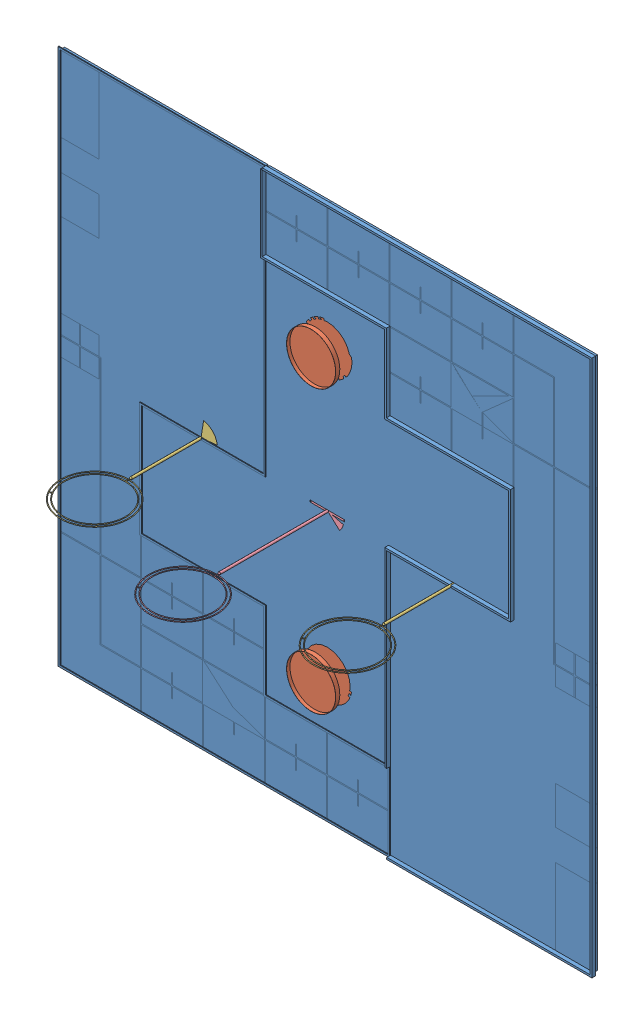
SolidWorks assembly playfieldasm, configuration Default. Lengths in mm.
Overall size (14100 14100 5035.59).
6 component instances, 4 part files, 13 mates.
Components (placement in the parent):
- playfield-1: playfield [Default] at (4070.2152 6513.5472 12026.2645) size (14100 14100 200.73)
- playfield1-1: playfield1 [Default] at (4070.2152 10213.5472 12020.8842) x (-0.989359 -0.145497 0) z (-0.145497 0.989359 0) size (1291.25 530.04 1291.25)
- playfield1-2: playfield1 [Default] at (4070.2152 2813.5472 12020.8842) x (0.949745 0.313024 0) z (0.313024 -0.949745 0) size (1291.25 530.04 1291.25)
- ss2-4: ss2 [Default] at (750.7466 6515.129 14815.9191) x (0.989949 0 0.141421) z (0.141421 0 -0.989949) size (1796 868 3819.99)
- ss2-5: ss2 [Default] at (7390.7462 6514.0213 14815.9191) x (0.989949 0 0.141421) z (0.141421 0 -0.989949) size (1796 868 3819.99)
- ss-4: ss [Default] at (4070.7462 6513.6426 15815.9191) x (0.989949 0 0.141421) z (0.141421 0 -0.989949) size (1877.72 868 4809.94)
Mates (geometry in assembly coordinates):
- Parallel1: parallel aligned: plane of playfield-1 through (4070.2152 6513.5472 11926.2645) normal (0 0 -1); plane of playfield1-1 through (4070.2152 10213.5472 11921.2645) normal (0 0 -1)
- Parallel2: parallel aligned: plane of playfield1-1 through (4070.2152 10213.5472 11921.2645) normal (0 0 -1); plane of playfield1-2 through (4070.2152 2813.5472 11921.2645) normal (0 0 -1)
- Concentric1: concentric anti-aligned: circle of playfield-1; circle of playfield1-1
- Distance2: distance = 0 mm aligned: plane of playfield1-1 through (3431.4606 10119.6105 12026.2645) normal (0 0 1); plane of playfield-1 through (4070.2152 6513.5472 12026.2645) normal (0 0 1)
- Concentric2: concentric anti-aligned: circle of playfield-1; circle of playfield1-2
- Coincident6: coincident aligned: plane of playfield-1 through (4070.2152 6513.5472 12026.2645) normal (0 0 1); plane of playfield1-2 through (4683.3944 3015.6434 12026.2645) normal (0 0 1)
- Parallel8: parallel aligned: plane of playfield-1 through (4070.2152 6513.5472 12026.2645) normal (0 0 1); plane of ss2-4 through (750.7466 6515.129 12026.2645) normal (0 0 1)
- Coincident21: coincident aligned: plane of playfield-1 through (4070.2152 6513.5472 11926.2645) normal (0 0 -1); plane of ss2-4 through (750.7466 6515.129 11926.2645) normal (0 0 -1)
- Coincident22: coincident aligned: plane of playfield-1 through (4070.2152 6513.5472 11926.2645) normal (0 0 -1); plane of ss2-5 through (7390.7462 6514.0213 11926.2645) normal (0 0 -1)
- Distance11: distance = 3260 mm: cylinder of ss2-5 through (7390.7462 6514.0213 14815.9191) axis (0 0 1) radius 30; cylinder of ss-4 through (4070.7462 6513.6426 15815.9191) axis (0 0 1) radius 30
- Lock9: lock: unknown of playfield-1; unknown of ss2-5
- Lock10: lock: unknown of playfield-1; unknown of ss2-4
- Lock11: lock: unknown of playfield-1; unknown of playfield1-2
